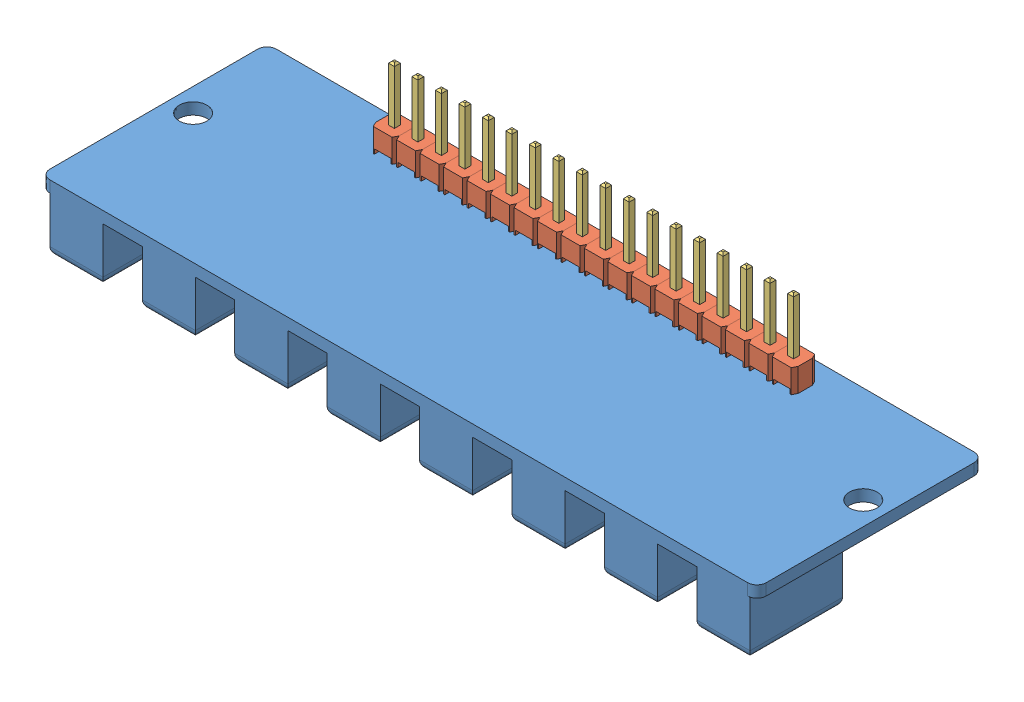
SolidWorks assembly Assem1, configuration Default. Lengths in mm.
Overall size (77.5 15.79 24.5).
38 component instances, 3 part files, 3 mates.
Components (placement in the parent):
- Raykha-1: Raykha [Default] at (56.2279 19.7049 -41.4444) size (77.5 7.25 24.5)
- Headers for Raykha-1: Headers for Raykha [3pin] at (33.7006 20.5007 -53.0297) size (45.72 11.54 2.54)
  - PlasticHolder-1: PlasticHolder [Default] at (0.8273 2.9943 2.6053) x (1 0 0) z (0 0 -1) size (2.54 2.54 2.54)
  - SinglePinStraight-1: SinglePinStraight [Default] at (0.8273 -2.5457 2.6053) size (0.64 11.54 0.64)
  - SinglePinStraight-2: SinglePinStraight [Default] at (3.3673 -2.5457 2.6053) size (0.64 11.54 0.64)
  - PlasticHolder-2: PlasticHolder [Default] at (3.3673 2.9943 2.6053) x (1 0 0) z (0 0 -1) size (2.54 2.54 2.54)
  - PlasticHolder-3: PlasticHolder [Default] at (5.9073 2.9943 2.6053) x (1 0 0) z (0 0 -1) size (2.54 2.54 2.54)
  - SinglePinStraight-3: SinglePinStraight [Default] at (5.9073 -2.5457 2.6053) size (0.64 11.54 0.64)
  - PlasticHolder-4: PlasticHolder [Default] at (8.4473 2.9943 2.6053) x (1 0 0) z (0 0 -1) size (2.54 2.54 2.54)
  - SinglePinStraight-4: SinglePinStraight [Default] at (8.4473 -2.5457 2.6053) size (0.64 11.54 0.64)
  - PlasticHolder-5: PlasticHolder [Default] at (10.9873 2.9943 2.6053) x (1 0 0) z (0 0 -1) size (2.54 2.54 2.54)
  - SinglePinStraight-5: SinglePinStraight [Default] at (10.9873 -2.5457 2.6053) size (0.64 11.54 0.64)
  - PlasticHolder-6: PlasticHolder [Default] at (13.5273 2.9943 2.6053) x (1 0 0) z (0 0 -1) size (2.54 2.54 2.54)
  - SinglePinStraight-6: SinglePinStraight [Default] at (13.5273 -2.5457 2.6053) size (0.64 11.54 0.64)
  - SinglePinStraight-7: SinglePinStraight [Default] at (16.0673 -2.5457 2.6053) size (0.64 11.54 0.64)
  - PlasticHolder-7: PlasticHolder [Default] at (16.0673 2.9943 2.6053) x (1 0 0) z (0 0 -1) size (2.54 2.54 2.54)
  - PlasticHolder-8: PlasticHolder [Default] at (18.6073 2.9943 2.6053) x (1 0 0) z (0 0 -1) size (2.54 2.54 2.54)
  - SinglePinStraight-8: SinglePinStraight [Default] at (18.6073 -2.5457 2.6053) size (0.64 11.54 0.64)
  - PlasticHolder-9: PlasticHolder [Default] at (21.1473 2.9943 2.6053) x (1 0 0) z (0 0 -1) size (2.54 2.54 2.54)
  - SinglePinStraight-9: SinglePinStraight [Default] at (21.1473 -2.5457 2.6053) size (0.64 11.54 0.64)
  - PlasticHolder-10: PlasticHolder [Default] at (23.6873 2.9943 2.6053) x (1 0 0) z (0 0 -1) size (2.54 2.54 2.54)
  - SinglePinStraight-10: SinglePinStraight [Default] at (23.6873 -2.5457 2.6053) size (0.64 11.54 0.64)
  - PlasticHolder-11: PlasticHolder [Default] at (26.2273 2.9943 2.6053) x (1 0 0) z (0 0 -1) size (2.54 2.54 2.54)
  - SinglePinStraight-11: SinglePinStraight [Default] at (26.2273 -2.5457 2.6053) size (0.64 11.54 0.64)
  - PlasticHolder-12: PlasticHolder [Default] at (28.7673 2.9943 2.6053) x (1 0 0) z (0 0 -1) size (2.54 2.54 2.54)
  - SinglePinStraight-12: SinglePinStraight [Default] at (28.7673 -2.5457 2.6053) size (0.64 11.54 0.64)
  - PlasticHolder-13: PlasticHolder [Default] at (31.3073 2.9943 2.6053) x (1 0 0) z (0 0 -1) size (2.54 2.54 2.54)
  - SinglePinStraight-13: SinglePinStraight [Default] at (31.3073 -2.5457 2.6053) size (0.64 11.54 0.64)
  - PlasticHolder-14: PlasticHolder [Default] at (33.8473 2.9943 2.6053) x (1 0 0) z (0 0 -1) size (2.54 2.54 2.54)
  - SinglePinStraight-14: SinglePinStraight [Default] at (33.8473 -2.5457 2.6053) size (0.64 11.54 0.64)
  - PlasticHolder-15: PlasticHolder [Default] at (36.3873 2.9943 2.6053) x (1 0 0) z (0 0 -1) size (2.54 2.54 2.54)
  - SinglePinStraight-15: SinglePinStraight [Default] at (36.3873 -2.5457 2.6053) size (0.64 11.54 0.64)
  - PlasticHolder-16: PlasticHolder [Default] at (38.9273 2.9943 2.6053) x (1 0 0) z (0 0 -1) size (2.54 2.54 2.54)
  - SinglePinStraight-16: SinglePinStraight [Default] at (38.9273 -2.5457 2.6053) size (0.64 11.54 0.64)
  - PlasticHolder-17: PlasticHolder [Default] at (41.4673 2.9943 2.6053) x (1 0 0) z (0 0 -1) size (2.54 2.54 2.54)
  - SinglePinStraight-17: SinglePinStraight [Default] at (41.4673 -2.5457 2.6053) size (0.64 11.54 0.64)
  - SinglePinStraight-18: SinglePinStraight [Default] at (44.0073 -2.5457 2.6053) size (0.64 11.54 0.64)
  - PlasticHolder-18: PlasticHolder [Default] at (44.0073 2.9943 2.6053) x (1 0 0) z (0 0 -1) size (2.54 2.54 2.54)
Mates (geometry in assembly coordinates):
- Coincident1: coincident: plane of Raykha-1 through (56.2279 20.9549 -41.4444) normal (0 1 0); plane of Headers for Raykha-1/PlasticHolder-14 through (66.5479 20.9549 -50.4244) normal (0 -1 0)
- Distance1: distance = 16 mm: plane of Headers for Raykha-1/PlasticHolder-18 through (78.9779 20.9549 -51.1944) normal (1 0 0); line of Raykha-1 through (94.9779 20.9549 -30.1944) axis (0 0 -1)
- Distance2: distance = 2 mm: plane of Headers for Raykha-1/PlasticHolder-16 through (71.6079 20.9549 -51.6944) normal (0 0 -1); plane of Raykha-1 through (17.4779 20.9549 -53.6944) normal (0 0 -1)
